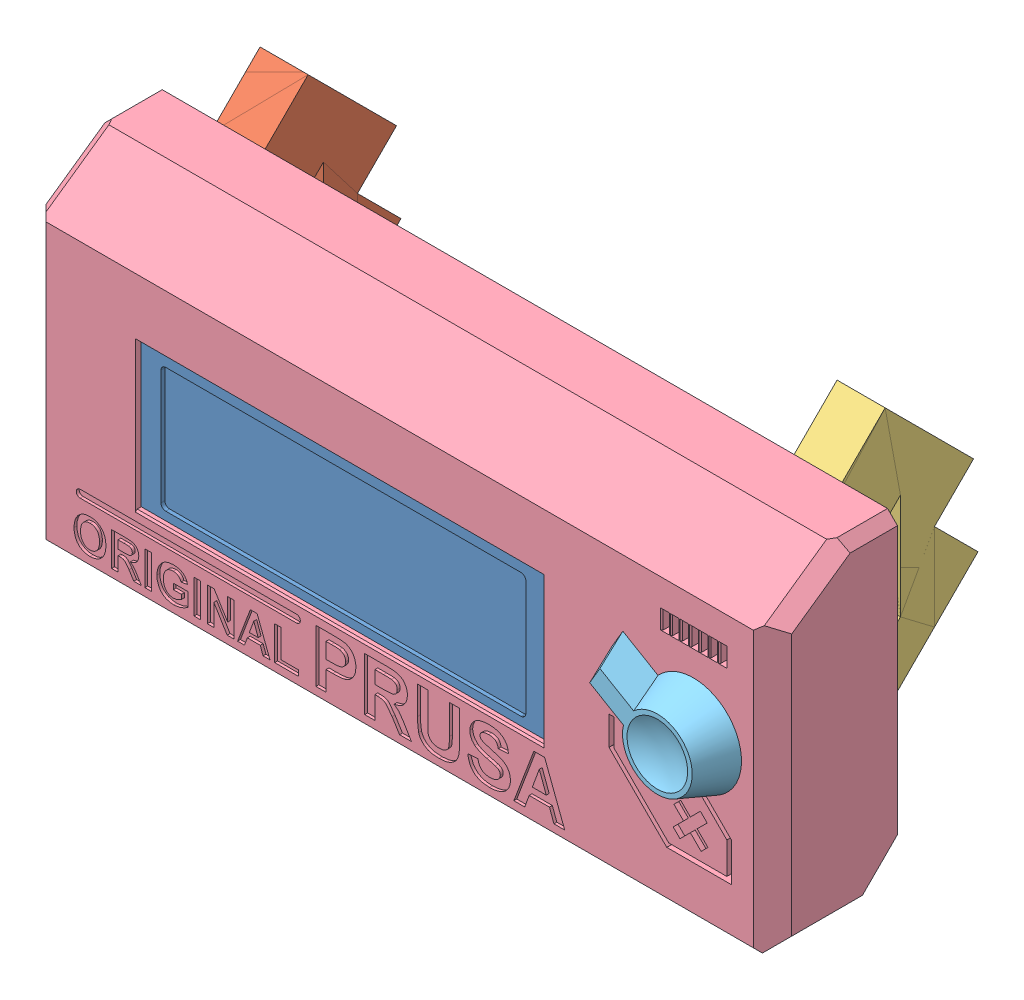
SolidWorks assembly LCD Assembly, configuration Default. Lengths in mm.
Overall size (155 84.29 80.03).
5 component instances, 5 part files, 11 mates.
Components (placement in the parent):
- LCD Board-1: LCD Board [Default] at (45.5138 89.6171 111.3378) size (150 63 29.71)
- lcd-supports1-1: lcd-supports1 [Default] at (-9.0362 59.8671 105.6378) x (0 -0.707107 0.707107) z (-1 0 0) size (65.69 47.48 20)
- lcd-supports2-1: lcd-supports2 [Default] at (110.9738 59.8671 105.6378) x (0 -0.707107 0.707107) z (-1 0 0) size (65.69 47.48 10)
- LCD-cover-ORIGINAL-MK3(R2)-1: LCD-cover-ORIGINAL-MK3(R2) [Default] at (45.2638 108.0671 124.7378) x (1 0 0) z (0 0 -1) size (155 70 26.06)
- LCD-knobR2-1: LCD-knobR2 [Default] at (107.8138 88.3671 125.7378) x (0.506601 0.862181 0) z (0 0 1) size (20 28.22 7.5)
Mates (geometry in assembly coordinates):
- Coincident1: coincident anti-aligned: plane of LCD Board-1 through (45.5138 89.6171 109.6378) normal (0 0 -1); plane of lcd-supports1-1 through (-4.0362 116.3671 109.6378) normal (0 0 1)
- Coincident5: coincident anti-aligned: plane of LCD Board-1 through (45.5138 89.6171 109.6378) normal (0 0 -1); plane of lcd-supports2-1 through (111.9738 61.3671 109.6378) normal (0 0 1)
- Parallel1: parallel anti-aligned: plane of LCD Board-1 through (-29.4862 62.1171 109.6378) normal (0 -1 0); plane of lcd-supports2-1 through (111.9738 61.3671 109.6378) normal (0 1 0)
- Parallel2: parallel anti-aligned: plane of LCD Board-1 through (-29.4862 62.1171 109.6378) normal (0 -1 0); plane of lcd-supports1-1 through (-8.0362 61.3671 109.6378) normal (0 1 0)
- Coincident7: coincident anti-aligned: plane of LCD Board-1 through (45.5138 89.6171 111.3378) normal (0 1 0); plane of lcd-supports1-1 through (-9.0362 89.6171 105.6378) normal (0 -1 0)
- Coincident8: coincident anti-aligned: plane of LCD Board-1 through (45.5138 89.6171 111.3378) normal (0 1 0); plane of lcd-supports2-1 through (110.9738 89.6171 105.6378) normal (0 -1 0)
- Concentric5: concentric aligned: circle of LCD Board-1; circle of LCD-cover-ORIGINAL-MK3(R2)-1
- Parallel3: parallel aligned: plane of LCD Board-1 through (-29.4862 117.1171 109.6378) normal (-1 0 0); plane of LCD-cover-ORIGINAL-MK3(R2)-1 through (-31.7362 122.7671 124.7378) normal (-1 0 0)
- Coincident11: coincident anti-aligned: plane of LCD Board-1 through (45.5138 89.6171 123.5378) normal (0 0 1); plane of LCD-cover-ORIGINAL-MK3(R2)-1 through (-16.2362 107.0671 123.5378) normal (0 0 -1)
- Concentric6: concentric anti-aligned: cylinder of LCD Board-1 through (107.8138 88.3671 122.5378) axis (0 0 -1) radius 3; cylinder of LCD-knobR2-1 through (107.8138 88.3671 125.6378) axis (0 0 1) radius 3.05
- Distance1: distance = 1 mm anti-aligned: plane of LCD-cover-ORIGINAL-MK3(R2)-1 through (-31.7362 112.5671 124.7378) normal (0 0 1); plane of LCD-knobR2-1 through (107.8138 88.3671 125.7378) normal (0 0 -1)
